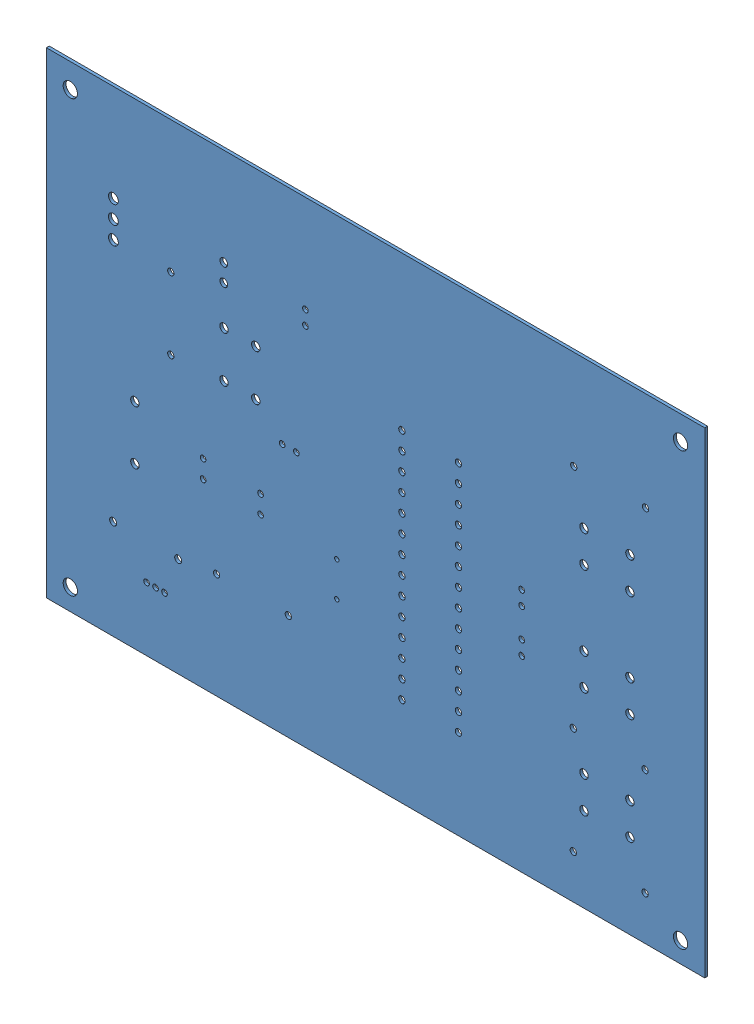
SolidWorks assembly PCB_Audio Output.step, configuration Default. Lengths in mm.
Overall size (93.18 67.43 0.41).
2 component instances, 1 part files, 0 mates.
Components (placement in the parent):
- Board.step-1: Board.step [Default] at origin size (93.18 67.43 0.41)
  - Open CASCADE STEP translator 6.8 1.1.1.step-1: Open CASCADE STEP translator 6.8 1.1.1.step [Default] at (0 0 -0.4115) size (93.18 67.43 0.41)
